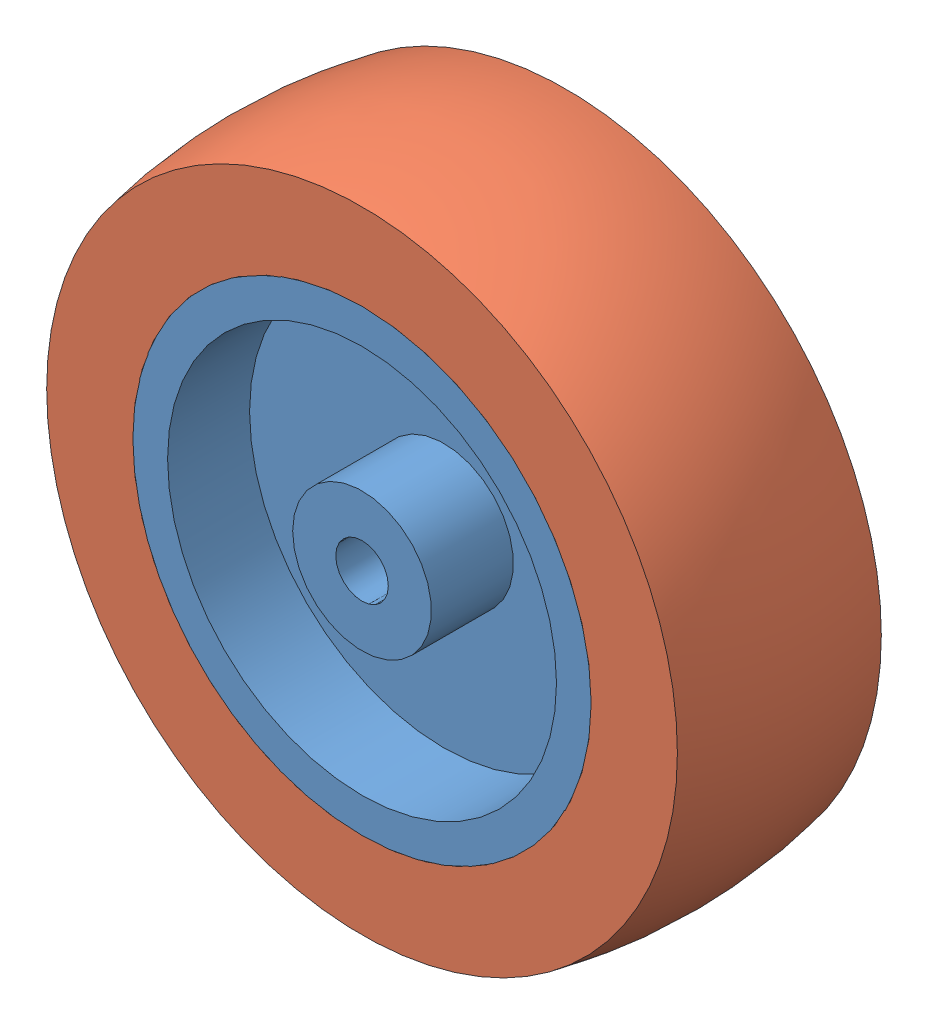
SolidWorks assembly Assem1, configuration Default. Lengths in mm.
Overall size (78.74 78.74 24.64).
2 component instances, 2 part files, 2 mates.
Components (placement in the parent):
- wheel_inner-2: wheel_inner [Default] at origin size (55.37 55.37 24.64)
- wheel_outter-1: wheel_outter [Default] at origin size (78.74 78.74 24.64)
Mates (geometry in assembly coordinates):
- Concentric1: concentric: cylinder of wheel_inner-2 through (0 0 12.319) axis (0 0 -1) radius 27.686; cylinder of wheel_outter-1 through (0 0 0) axis (0 0 -1) radius 27.686
- Coincident7: coincident aligned: plane of wheel_inner-2 through (0 0 12.319) normal (0 0 1); plane of wheel_outter-1 through (0 38.1 12.319) normal (0 0 1)
